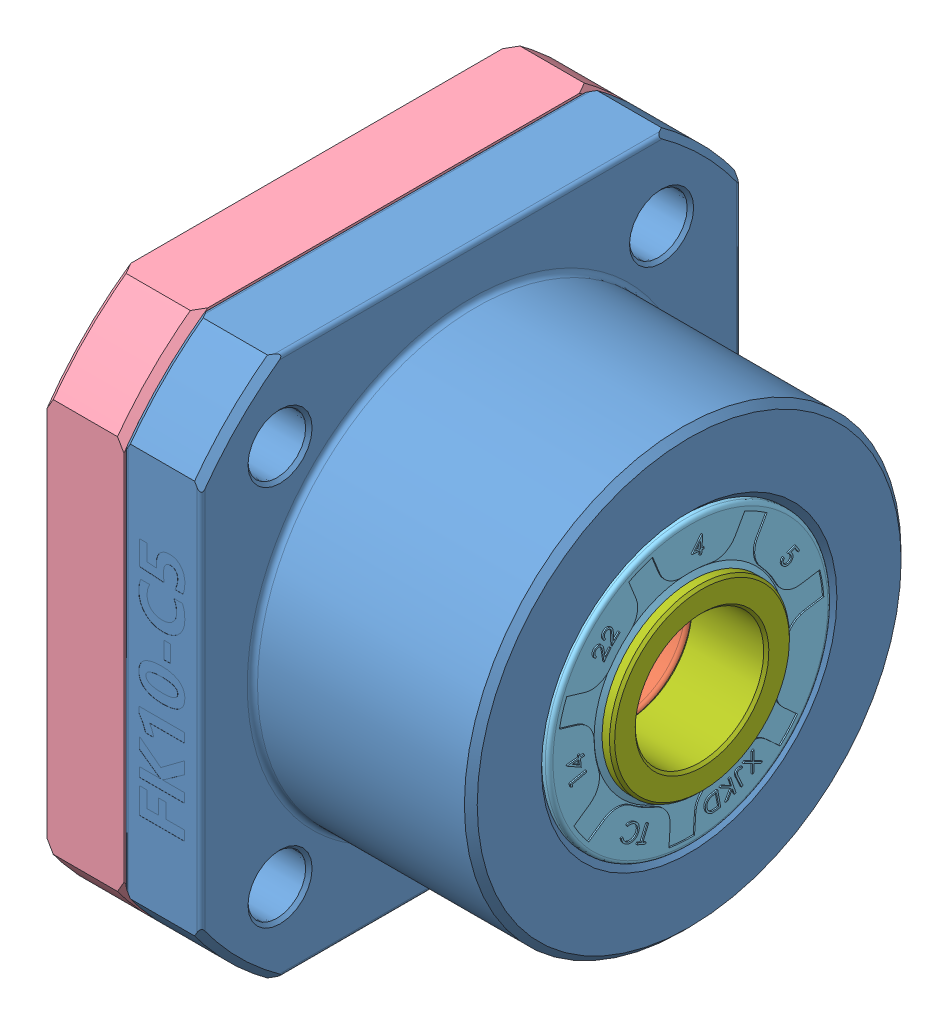
SolidWorks assembly FK10-C5, configuration По умолчанию. Lengths in mm.
Overall size (31 42 42).
16 component instances, 8 part files, 23 mates.
Components (placement in the parent):
- FK10-C5-1: FK10-C5 [По умолчанию] at origin size (23 42 42)
- 7000C-1: 7000C [По умолчанию] at (7.5224 -0.6816 -0.8667) x (1 0 0) z (0 0.098321 0.995155) size (8 26 26)
  - 7000-C-1: 7000-C [По умолчанию] at origin size (8 26 26)
  - Сепаратор-1: Сепаратор [По умолчанию] at (-1.5224 0.5931 0.9295) x (0 0 -1) z (1 0 0) size (19 19 8)
- 7000C-2: 7000C [По умолчанию] at (12.4776 -0.9627 0.5375) x (-1 0 0) z (0 0.473836 -0.880613) size (8 26 26)
  - 7000-C-1: 7000-C [По умолчанию] at origin size (8 26 26)
  - Сепаратор-1: Сепаратор [По умолчанию] at (-1.5224 0.5931 0.9295) x (0 0 -1) z (1 0 0) size (19 19 8)
- FK10-C5_Крышка-1: FK10-C5_Крышка [По умолчанию] at (-6 0 0) size (8 42 42)
- Манжета 14х22x4-1: Манжета 14х22x4 [По умолчанию] at (-6 0 0) size (4.23 22 22)
- Манжета 14х22x4-2: Манжета 14х22x4 [По умолчанию] at (23.1 0 0) x (-1 0 0) z (0 0.373812 -0.927504) size (4.23 22 22)
- Кольцо_верх-1: Кольцо_верх [По умолчанию] at (-7 0 0) x (1 0 0) z (0 -0.021671 0.999765) size (9 14 14)
- Кольцо_низ-1: Кольцо_низ [По умолчанию] at (18 0 0) x (1 0 0) z (0 0.654573 0.755999) size (6 14 14)
- Винт M4x5-1: Винт M4x5 [По умолчанию] at (-5.8 -15.9748 -5.8143) x (1 0 0) z (0 -0.836465 0.54802) size (9.35 7.06 7.06)
- Винт M4x5-2: Винт M4x5 [По умолчанию] at (-5.8 -5.8143 15.9748) x (1 0 0) z (0 0.997919 -0.064488) size (9.35 7.06 7.06)
- Винт M4x5-3: Винт M4x5 [По умолчанию] at (-5.8 15.9748 5.8143) x (1 0 0) z (0 0.009771 0.999952) size (9.35 7.06 7.06)
- Винт M4x5-4: Винт M4x5 [По умолчанию] at (-5.8 5.8143 -15.9748) x (1 0 0) z (0 0.897015 -0.442) size (9.35 7.06 7.06)
Mates (geometry in assembly coordinates):
- Концентричный1: concentric aligned: cylinder of FK10-C5-1 through (0 0 0) axis (-1 0 0) radius 13; cylinder of 7000C-2/7000-C-1 through (34.6375 0 0) axis (-1 0 0) radius 13
- Совпадение1: coincident anti-aligned: plane of FK10-C5-1 through (18 11.5 0) normal (-1 0 0); plane of 7000C-2/7000-C-1 through (18 10.017 5.3899) normal (1 0 0)
- Концентричный2: concentric anti-aligned: cylinder of FK10-C5-1 through (0 0 0) axis (-1 0 0) radius 13; cylinder of 7000C-1/7000-C-1 through (-14.6375 0 0) axis (1 0 0) radius 13
- Совпадение2: coincident anti-aligned: plane of 7000C-1/7000-C-1 through (10 12.6385 -1.2487) normal (1 0 0); plane of 7000C-2/7000-C-1 through (10 11.1838 6.0177) normal (-1 0 0)
- Концентричный3: concentric anti-aligned: cylinder of FK10-C5-1 through (0 0 0) axis (-1 0 0) radius 13; cone of FK10-C5_Крышка-1 through (2 0 0) axis (1 0 0)
- Совпадение3: coincident anti-aligned: plane of FK10-C5-1 through (0 13.5 0) normal (-1 0 0); plane of FK10-C5_Крышка-1 through (0 25.5 0) normal (1 0 0)
- Концентричный4: concentric aligned: cylinder of FK10-C5-1 through (0 15.9748 5.8143) axis (-1 0 0) radius 1.65; cylinder of FK10-C5_Крышка-1 through (-6 15.9748 5.8143) axis (-1 0 0) radius 2.25
- Концентричный5: concentric aligned: cylinder of FK10-C5_Крышка-1 through (-6 0 0) axis (-1 0 0) radius 11; cylinder of Манжета 14х22x4-1 through (-6 0 0) axis (-1 0 0) radius 11
- Совпадение4: coincident aligned: plane of FK10-C5_Крышка-1 through (-6 11.5 0) normal (-1 0 0); plane of Манжета 14х22x4-1 through (-6 7.5 0) normal (-1 0 0)
- Концентричный6: concentric anti-aligned: cylinder of FK10-C5-1 through (0 0 0) axis (-1 0 0) radius 11; cylinder of Манжета 14х22x4-2 through (23.1 0 0) axis (1 0 0) radius 11
- Совпадение5: coincident aligned: plane of FK10-C5-1 through (23 16.5 0) normal (1 0 0); plane of Манжета 14х22x4-2 through (23 6.8635 2.7662) normal (1 0 0)
- Концентричный7: concentric aligned: cylinder of FK10-C5_Крышка-1 through (-6 0 0) axis (-1 0 0) radius 11; cylinder of Кольцо_верх-1 through (-7 0 0) axis (-1 0 0) radius 7
- Совпадение6: coincident anti-aligned: plane of 7000C-1/7000-C-1 through (2 7.3641 -0.7276) normal (-1 0 0); plane of Кольцо_верх-1 through (2 5.1988 0.1127) normal (1 0 0)
- Концентричный8: concentric aligned: cylinder of 7000C-2/7000-C-1 through (34.6375 0 0) axis (-1 0 0) radius 11.375; cylinder of Кольцо_низ-1 through (18 0 0) axis (-1 0 0) radius 7
- Совпадение7: coincident anti-aligned: plane of 7000C-2/7000-C-1 through (18 6.5165 3.5064) normal (1 0 0); plane of Кольцо_низ-1 through (18 5.1408 -4.4511) normal (-1 0 0)
- Концентричный9: concentric aligned: cylinder of FK10-C5-1 through (0 15.9748 5.8143) axis (-1 0 0) radius 1.65; cylinder of Винт M4x5-3 through (-2.7 15.9748 5.8143) axis (-1 0 0) radius 1.95
- Совпадение8: coincident anti-aligned: plane of FK10-C5_Крышка-1 through (-1.8 19.6748 5.8143) normal (-1 0 0); plane of Винт M4x5-3 through (-1.8 19.2746 5.7821) normal (1 0 0)
- Концентричный10: concentric aligned: cylinder of FK10-C5-1 through (0 5.8143 -15.9748) axis (-1 0 0) radius 1.65; cylinder of Винт M4x5-4 through (-2.7 5.8143 -15.9748) axis (-1 0 0) radius 1.95
- Совпадение9: coincident anti-aligned: plane of FK10-C5_Крышка-1 through (-1.8 9.5143 -15.9748) normal (-1 0 0); plane of Винт M4x5-4 through (-1.8 4.3557 -18.9349) normal (1 0 0)
- Концентричный11: concentric aligned: cylinder of FK10-C5-1 through (0 -5.8143 15.9748) axis (-1 0 0) radius 1.65; cylinder of Винт M4x5-2 through (-2.7 -5.8143 15.9748) axis (-1 0 0) radius 1.95
- Совпадение10: coincident anti-aligned: plane of FK10-C5_Крышка-1 through (-1.8 -2.1143 15.9748) normal (-1 0 0); plane of Винт M4x5-2 through (-1.8 -6.0272 12.6816) normal (1 0 0)
- Концентричный12: concentric aligned: cylinder of FK10-C5-1 through (0 -15.9748 -5.8143) axis (-1 0 0) radius 1.65; cylinder of Винт M4x5-1 through (-2.7 -15.9748 -5.8143) axis (-1 0 0) radius 1.95
- Совпадение11: coincident anti-aligned: plane of FK10-C5_Крышка-1 through (-1.8 -12.2748 -5.8143) normal (-1 0 0); plane of Винт M4x5-1 through (-1.8 -14.1663 -3.054) normal (1 0 0)
